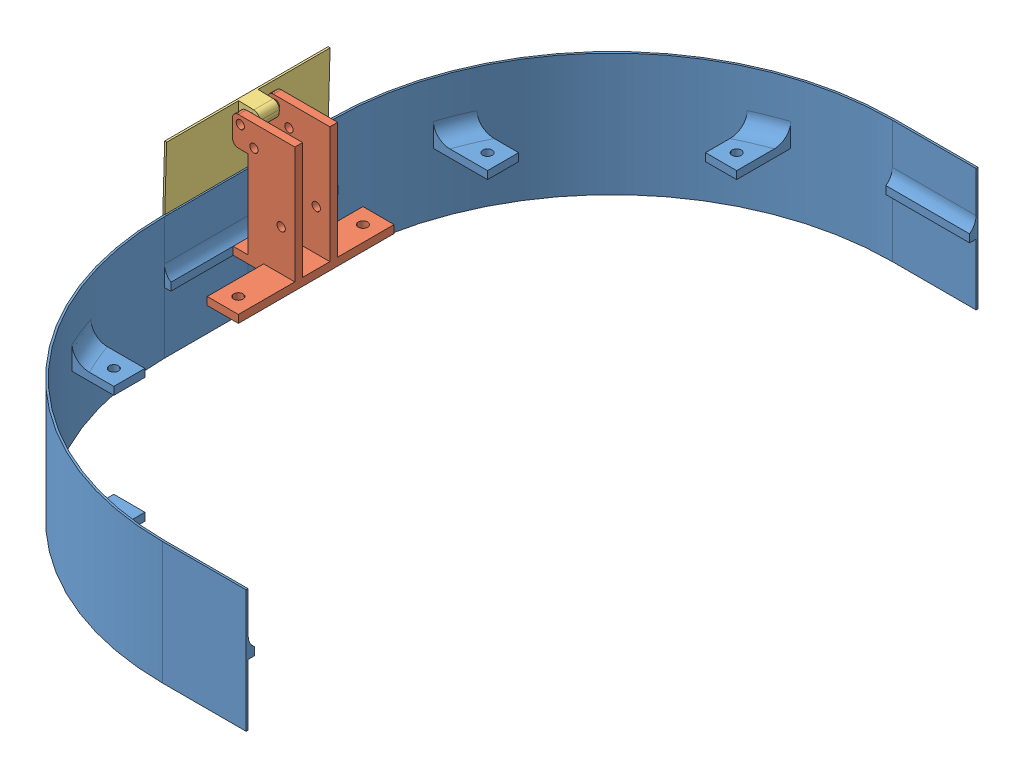
SolidWorks assembly Assem1, configuration Default. Lengths in mm.
Overall size (150.57 75.98 298.45).
4 component instances, 3 part files, 8 mates.
Components (placement in the parent):
- BumperMountsV2-1: BumperMountsV2 [Default] at (98.558 65.2988 210.1419) size (149.22 50 149.22)
- BumperMountsV2-3: BumperMountsV2 [Default] at (98.558 65.2988 210.1419) x (0 0 -1) z (1 0 0) size (149.22 50 149.22)
- limitswitchmount-1: limitswitchmount [Default] at (-28.442 71.6488 210.1419) x (0 0 -1) z (1 0 0) size (63.5 50.8 27.78)
- limitplate-1: limitplate [Default] at (-50.5011 97.2153 210.1419) x (0 0 1) z (-0.999598 0.028351 0) size (66.67 50.8 9.52)
Mates (geometry in assembly coordinates):
- Coincident1: coincident aligned: plane of BumperMountsV2-1 through (98.558 96.6488 210.1419) normal (0 1 0); plane of BumperMountsV2-3 through (98.558 96.6488 210.1419) normal (0 1 0)
- Coincident3: coincident aligned: plane of BumperMountsV2-1 through (-49.8733 96.6488 210.1419) normal (1 0 0); plane of BumperMountsV2-3 through (-49.8733 96.6488 210.1419) normal (1 0 0)
- Coincident4: coincident anti-aligned: plane of BumperMountsV2-1 through (98.558 96.6488 210.1419) normal (0 0 1); plane of BumperMountsV2-3 through (98.558 74.8238 210.1419) normal (0 0 -1)
- Coincident5: coincident anti-aligned: plane of BumperMountsV2-1 through (-49.8733 96.6488 210.1419) normal (1 0 0); plane of limitswitchmount-1 through (-49.8733 74.8238 201.4107) normal (-1 0 0)
- Width1: width aligned: plane of limitswitchmount-1 through (-28.442 74.8238 241.8919) normal (0 0 1); plane of BumperMountsV2-1 through (-28.442 74.8238 178.3919) normal (0 0 -1); plane of limitswitchmount-1 through (98.558 74.8238 140.2919) normal (0 0 1); plane of BumperMountsV2-3 through (98.558 74.8238 279.9919) normal (0 0 -1)
- Coincident6: coincident aligned: plane of BumperMountsV2-1 through (-84.9456 71.6488 210.1419) normal (0 -1 0); plane of limitswitchmount-1 through (-28.442 71.6488 210.1419) normal (0 -1 0)
- Concentric1: concentric anti-aligned: cylinder of limitswitchmount-1 through (-44.317 119.2738 201.4107) axis (0 0 -1) radius 1.7; cylinder of limitplate-1 through (-44.317 119.2738 210.1419) axis (0 0 1) radius 1.7
- Width2: width anti-aligned: plane of limitplate-1 through (-43.7003 118.6211 214.1107) normal (0 0 1); plane of limitswitchmount-1 through (-43.7003 118.6211 206.1732) normal (0 0 -1); plane of limitplate-1 through (-22.092 74.8238 201.4107) normal (0 0 -1); plane of limitswitchmount-1 through (-22.092 74.8238 218.8732) normal (0 0 1)
